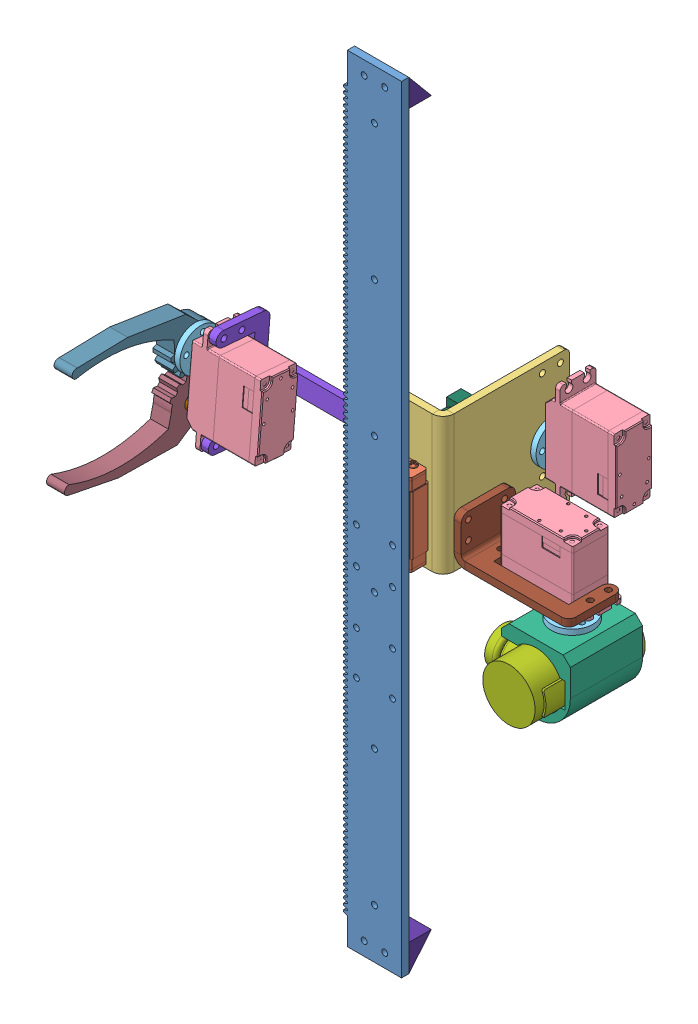
SolidWorks assembly Arm Assembly, configuration 預設. Lengths in mm.
23 component instances, 17 part files, 77 mates.
Components (placement in the parent):
- horrizontal rack-1: horrizontal rack [預設] at (0 0 -4) x (0 1 0) z (1 0 0) size (430 4 32.25)
- MGN12H-3: MGN12H [Default] at (0 -2.634 -4) x (1 0 0) z (0 1 0) size (27 10 48.55)
- horrizotal servo frame-1: horrizotal servo frame [預設] at (15 -28.634 -18) x (0 1 0) z (0 0 -1) size (75.71 38 70)
- UART Servo-4: UART Servo [預設] at (55.75 -17.934 -44.05) x (-1 0 0) z (0 -1 0) size (56 22.53 44.45)
- SMS Servo Disc-4: SMS Servo Disc [預設] at (65.425 -39.384 -44.05) x (0.954716 0 0.297519) z (0 1 0) size (23 23 6)
- Camera Mount 2-1: Camera Mount 2 [預設] at (65.425 -58.384 -24.05) x (0 1 0) z (0 0 -1) size (38 47 40)
- LifeCam Studio-2: LifeCam Studio [Default] at (65.425 -58.384 -70.05) x (0.017996 0.999838 0) z (0 0 -1) size (29 41 61)
- UART Servo-5: UART Servo [預設] at (42.45 17.321 -77) x (0 1 0) z (-1 0 0) size (56 22.53 44.45)
- gripper servo frame-2: gripper servo frame [預設] at (-91.15 -14.2051 5.1529) x (0 0.996386 -0.084938) z (1 0 0) size (57.5 85 108.15)
- UART Servo-6: UART Servo [預設] at (-84.45 13.6384 -6.705) x (0 -0.996386 0.084938) z (-1 0 0) size (56 22.53 44.45)
- gripper right part-1: gripper right part [預設] at (-107.75 -3.5402 -21.8506) x (0 0.996386 -0.084938) z (1 0 0) size (27.08 24.17 3)
- M3x5mm_toothed_plastic-4: M3x5mm_toothed_plastic [預設] at (-91.15 15.4709 -23.4712) x (0 -0.820288 0.57195) z (-1 0 0) size (5.77 5 11)
- SMS Servo Disc-5: SMS Servo Disc [預設] at (-106.75 23.2784 -7.5267) x (0 0.154092 0.988056) z (1 0 0) size (23 23 6)
- cam servo frame-2: cam servo frame [預設] at (27 -24.634 -53.05) x (1 0 0) z (0 1 0) size (63.5 30 25)
- MGNR12X400mm-1: MGNR12X400mm [Default] at (0 200 -8) x (-1 0 0) z (0 -1 0) size (12 8 400)
- gear gripper left-1: gear gripper left [預設] at (-116.75 -8.9582 7.3711) x (0 0.999873 -0.015967) z (1 0 0) size (30.5 83.97 10)
- gear gripper right-1: gear gripper right [預設] at (-106.75 32.198 4.2394) x (0 -0.988056 0.154092) z (-1 0 0) size (30.51 84.01 10)
- CHR-GM25-370-1: CHR-GM25-370 [預設] at (-26.35 -12.634 -73.8) x (-0.000569 1 0) z (0 0 1) size (27.5 25 72.5)
- mg25 moter mount-1: mg25 moter mount [預設] at (-10 -12.634 -21) x (0 1 0) z (0 0 -1) size (36 52.35 3)
- SMS Servo Disc-8: SMS Servo Disc [預設] at (21 7.646 -77) x (0 -1 0.000402) z (1 0 0) size (23 23 6)
- M3x5mm_toothed_plastic-5: M3x5mm_toothed_plastic [預設] at (-96.15 15.4709 -23.4712) x (0 -0.820288 0.57195) z (-1 0 0) size (5.77 5 11)
- limit block-1: limit block [預設] at (-15 -200 -4) x (0 -1 0) z (1 0 0) size (15 12.5 30)
- limit block-2: limit block [預設] at (15 200 -4) x (0 1 0) z (-1 0 0) size (15 12.5 30)
Mates (geometry in assembly coordinates):
- 重合/共線/共點1: coincident: point of Chassis-1/Chassis Top Frame-1
- 重合/共線/共點2: coincident anti-aligned: plane of Chassis-1/Chassis Down Frame-1 through (0 0 147.2243) normal (0 -1 0)
- 重合/共線/共點3: coincident anti-aligned: plane of Chassis-1/Chassis Top Frame-1 through (85 72 0) normal (0 0 -1)
- 重合/共線/共點4: coincident anti-aligned: plane of Chassis-1/Chassis Top Frame-1 through (0 72 147.2243) normal (0 1 0); plane of V-Slot 40x40x300 Linear Rail-1 through (0 72 50) normal (0 -1 0)
- 同軸心1: concentric aligned: circle of Chassis-1/Chassis Top Frame-1; circle of V-Slot 40x40x300 Linear Rail-1
- 同軸心2: concentric anti-aligned: circle of Chassis-1/Chassis Top Frame-1; circle of V-Slot 40x40x300 Linear Rail-1
- 平行相距14: distance = 44 mm anti-aligned: plane of Chassis-1/Chassis Top Frame-1 through (0 72 147.2243) normal (0 1 0); plane of r20 servo case-2 through (10 116 60) normal (0 -1 0)
- 同軸心51: concentric aligned: circle of Servo Hub-2; circle of r20-1
- 重合/共線/共點58: coincident anti-aligned: plane of Servo Hub-2 through (-32.67 83.45 42.755) normal (0 1 0); plane of r20-1 through (-32.67 83.45 42.755) normal (0 -1 0)
- 平行22: parallel anti-aligned: line of horrizontal rack-1 through (149.665 369.55 -6) axis (-1 0 0); line of MGN12H-300-2/MGNR12-1 through (-150.335 358.0118 -14) axis (1 0 0)
- 重合/共線/共點104: coincident anti-aligned: plane of horrizontal rack-1 through (0 354.55 -6) normal (0 0 -1); plane of MGN12H-300-2/MGNR12-1 through (-150.335 346.3118 -6) normal (0 0 1)
- 重合/共線/共點105: coincident aligned: plane of horrizontal rack-1 through (149.665 354.55 -3) normal (1 0 0); plane of MGN12H-300-2/MGNR12-1 through (149.665 358.3118 -12) normal (1 0 0)
- 同軸心93: concentric anti-aligned: circle of MGN12H-300-2/MGNR12-1; circle of MGN12H-3
- 同軸心94: concentric aligned: cylinder of MGN12H-300-2/MGNR12-1; cylinder of MGN12H-3 through (-510.5136 559.1395 -370.2037) axis (-0.015138 -0.976168 0.216489) radius 0.559
- 同軸心98: concentric anti-aligned: circle of horrizontal rack-1; circle of MGN12H-300-2/MGNR12-1
- 同軸心104: concentric anti-aligned: circle of MGN12H-3; circle of horrizotal servo frame-1
- 同軸心105: concentric anti-aligned: circle of MGN12H-3; circle of horrizotal servo frame-1
- 同軸心112: concentric aligned: circle of UART Servo-4; circle of SMS Servo Disc-4
- 重合/共線/共點115: coincident anti-aligned: plane of UART Servo-4 through (65.425 -39.339 -44.05) normal (0 -1 0); plane of SMS Servo Disc-4 through (65.425 -39.339 -44.05) normal (0 1 0)
- 同軸心120: concentric anti-aligned: circle of SMS Servo Disc-4; circle of Camera Mount 2-1
- 重合/共線/共點118: coincident anti-aligned: plane of SMS Servo Disc-4 through (65.425 -40.839 -44.05) normal (0 -1 0); plane of Camera Mount 2-1 through (84.425 -40.839 -64.05) normal (0 1 0)
- 同軸心125: concentric aligned: cylinder of Camera Mount 2-1 through (65.425 -59.839 -24.049) axis (0 0 -1) radius 15; cylinder of LifeCam Studio-2 through (65.425 -59.839 -31.05) axis (0 0 -1) radius 14.5
- 重合/共線/共點123: coincident anti-aligned: plane of Camera Mount 2-1 through (65.425 -59.839 -44.05) normal (0 0 1); plane of LifeCam Studio-2 through (81.8199 -65.885 -44.05) normal (0 0 -1)
- 重合/共線/共點124: coincident: plane of Camera Mount 2-1 through (81.425 -66.839 -44.05) normal (0 1 0); line of LifeCam Studio-2 through (79.2543 -66.839 -15.05) axis (0 0 -1)
- 平行25: parallel: plane of gripper servo frame-2; line of gripper right part-1 through (-106.75 18.021 -135) axis (0 -1 0)
- 同軸心151: concentric anti-aligned: circle of UART Servo-6; circle of SMS Servo Disc-5
- 重合/共線/共點144: coincident anti-aligned: plane of MGN12H-3 through (-13.5 12.111 -17) normal (0 0 -1); plane of horrizotal servo frame-1 through (15 -30.089 -17) normal (0 0 1)
- 同軸心160: concentric aligned: circle of MGN12H-3; cylinder of MGNR12X400mm-1 through (6 -200 -10) axis (0 1 0) radius 0.559
- 同軸心161: concentric aligned: circle of MGN12H-3; cylinder of MGNR12X400mm-1 through (-6 -200 -10) axis (0 1 0) radius 0.559
- 同軸心171: concentric aligned: cylinder of SMS Servo Disc-5 through (-103.75 -11.0946 -145.0846) axis (-1 0 0) radius 1.5; circle of gear gripper right-1
- 同軸心173: concentric anti-aligned: circle of SMS Servo Disc-5; circle of gear gripper right-1
- 重合/共線/共點166: coincident anti-aligned: plane of gripper right part-1 through (-106.75 22.021 -131) normal (-1 0 0); plane of gear gripper left-1 through (-106.75 11.8045 -157.8294) normal (1 0 0)
- 同軸心174: concentric anti-aligned: circle of gripper right part-1; circle of gear gripper left-1
- 齒輪結合1: gear = 3.2 : 3.2 mm: cylinder of gear gripper left-1 through (-106.75 22.021 -147.17) axis (-1 0 0) radius 1.6; cylinder of gear gripper right-1 through (-106.75 -3.484 -147.55) axis (-1 0 0) radius 1.6
- 重合/共線/共點169: coincident anti-aligned: plane of UART Servo-4 through (75.75 -26.089 -54.05) normal (0 1 0); plane of cam servo frame-2 through (27 -26.089 -53.05) normal (0 -1 0)
- 重合/共線/共點170: coincident anti-aligned: plane of horrizotal servo frame-1 through (21 -30.089 -18) normal (1 0 0); plane of cam servo frame-2 through (21 -26.089 -53.05) normal (-1 0 0)
- 同軸心181: concentric aligned: circle of horrizotal servo frame-1; circle of cam servo frame-2
- 同軸心182: concentric aligned: circle of horrizotal servo frame-1; circle of cam servo frame-2
- 同軸心184: concentric aligned: cylinder of horrizotal servo frame-1 through (10 -14.089 -21) axis (0 0 -1) radius 1.6; circle of mg25 moter mount-1
- 同軸心185: concentric aligned: circle of horrizotal servo frame-1; circle of mg25 moter mount-1
- 重合/共線/共點177: coincident anti-aligned: plane of horrizotal servo frame-1 through (15 -30.089 -21) normal (0 0 -1); plane of mg25 moter mount-1 through (-26.35 -14.089 -21) normal (0 0 1)
- 同軸心186: concentric aligned: cylinder of CHR-GM25-370-1 through (-26.35 -14.089 -12) axis (0 0 -1) radius 2; cylinder of mg25 moter mount-1 through (-26.35 -14.089 -24) axis (0 0 -1) radius 4
- 重合/共線/共點179: coincident anti-aligned: plane of CHR-GM25-370-1 through (-26.35 -14.089 -24) normal (0 0 1); plane of mg25 moter mount-1 through (-26.35 -14.089 -24) normal (0 0 -1)
- 重合/共線/共點180: coincident anti-aligned: plane of UART Servo-6 through (-100.75 6.191 -147.55) normal (-1 0 0); plane of SMS Servo Disc-5 through (-100.75 -3.484 -147.55) normal (1 0 0)
- 重合/共線/共點181: coincident anti-aligned: plane of SMS Servo Disc-5 through (-106.75 -3.484 -147.55) normal (-1 0 0); plane of gear gripper right-1 through (-106.75 6.7261 -158.2155) normal (1 0 0)
- 重合/共線/共點182: coincident anti-aligned: plane of gripper servo frame-2 through (-91.15 34.941 -157) normal (-1 0 0); plane of M3x5mm_toothed_plastic-4 through (-91.15 2.941 -131) normal (1 0 0)
- 同軸心191: concentric aligned: circle of horrizotal servo frame-1; circle of UART Servo-5
- 重合/共線/共點187: coincident anti-aligned: plane of UART Servo-5 through (22.5 6.191 -77) normal (-1 0 0); plane of SMS Servo Disc-8 through (22.5 6.191 -77) normal (1 0 0)
- 平行28: parallel: line of horrizotal servo frame-1 through (17 -27.089 -87) axis (0 1 0); plane of UART Servo-5 through (43.6 15.866 -87) normal (0 0 -1)
- 重合/共線/共點188: coincident anti-aligned: plane of horrizotal servo frame-1 through (21 -30.089 -18) normal (1 0 0); plane of SMS Servo Disc-8 through (21 6.191 -77) normal (-1 0 0)
- 重合/共線/共點191: coincident anti-aligned: plane of horrizotal servo frame-1 through (17 -30.089 -18) normal (-1 0 0); plane of gripper servo frame-2 through (17 34.941 -157) normal (1 0 0)
- 同軸心203: concentric aligned: circle of horrizotal servo frame-1; circle of SMS Servo Disc-8
- 限制距離10: limit distance = 179.934 mm aligned: plane of MGNR12X400mm-1 through (-6 200 -10) normal (0 1 0); plane of MGN12H-3 through (6 20.066 -10) normal (0 1 0)
- 重合/共線/共點192: coincident anti-aligned: plane of gripper servo frame-2 through (-91.15 34.941 -157) normal (-1 0 0); plane of UART Servo-6 through (-91.15 -13.809 -157.55) normal (1 0 0)
- 重合/共線/共點193: coincident anti-aligned: plane of M3x5mm_toothed_plastic-4 through (-96.15 2.941 -131) normal (-1 0 0); plane of M3x5mm_toothed_plastic-5 through (-96.15 2.941 -131) normal (1 0 0)
- 同軸心204: concentric aligned: circle of M3x5mm_toothed_plastic-4; cylinder of M3x5mm_toothed_plastic-5 through (-90.15 2.941 -131) axis (-1 0 0) radius 1.5
- 重合/共線/共點195: coincident aligned: plane of gear gripper left-1 through (-116.75 11.8045 -157.8294) normal (-1 0 0); plane of gear gripper right-1 through (-116.75 6.7261 -158.2155) normal (-1 0 0)
- 同軸心207: concentric anti-aligned: circle of gripper servo frame-2; circle of UART Servo-6
- 同軸心208: concentric anti-aligned: cylinder of gripper servo frame-2 through (-91.15 -18.559 -142.55) axis (-1 0 0) radius 1.65; circle of UART Servo-6
- 同軸心209: concentric anti-aligned: cylinder of gripper servo frame-2 through (13 6.191 -77) axis (-1 0 0) radius 1.25; circle of SMS Servo Disc-8
- 同軸心210: concentric anti-aligned: circle of gripper right part-1; circle of M3x5mm_toothed_plastic-5
- 同軸心211: concentric anti-aligned: circle of gripper servo frame-2; circle of M3x5mm_toothed_plastic-4
- 同軸心212: concentric anti-aligned: circle of UART Servo-4; circle of cam servo frame-2
- 同軸心213: concentric anti-aligned: circle of UART Servo-4; cylinder of cam servo frame-2 through (80.5 -26.089 -49.05) axis (0 -1 0) radius 1.65
- 平行30: parallel anti-aligned: plane of Camera Mount 2-1 through (65.425 -59.839 -24.05) normal (0 0 1); plane of cam servo frame-2 through (21 -22.089 -53.05) normal (0 0 -1)
- 重合/共線/共點196: coincident anti-aligned: plane of horrizontal rack-1 through (0 0 -4) normal (0 0 -1); plane of MGNR12X400mm-1 through (6 -200 -4) normal (0 0 1)
- 同軸心214: concentric aligned: circle of horrizontal rack-1; cylinder of MGNR12X400mm-1 through (0 -187.5 -12) axis (0 0 -1) radius 1.75
- 同軸心215: concentric aligned: circle of horrizontal rack-1; cylinder of MGNR12X400mm-1 through (0 -112.5 -12) axis (0 0 -1) radius 1.75
- 同軸心219: concentric anti-aligned: circle of horrizontal rack-1; circle of limit block-1
- 同軸心220: concentric anti-aligned: circle of horrizontal rack-1; cylinder of limit block-1 through (5.7 -207.5 -34) axis (0 0 1) radius 2.1
- 重合/共線/共點198: coincident anti-aligned: plane of horrizontal rack-1 through (0 0 -4) normal (0 0 -1); plane of limit block-1 through (15 -200 -4) normal (0 0 1)
- 同軸心221: concentric anti-aligned: circle of horrizontal rack-1; circle of limit block-2
- 同軸心222: concentric aligned: circle of horrizontal rack-1; circle of limit block-2
- 重合/共線/共點199: coincident anti-aligned: plane of horrizontal rack-1 through (0 0 -4) normal (0 0 -1); plane of limit block-2 through (-15 200 -4) normal (0 0 1)
- 重合/共線/共點201: coincident aligned: plane of horrizontal rack-1 through (0 0 0) normal (0 0 1)
- 相互對稱1: symmetric aligned: plane of horrizontal rack-1 through (0 215 -4) normal (0 1 0); plane of horrizontal rack-1 through (0 -215 -4) normal (0 -1 0)
- 相互對稱2: symmetric aligned: plane of horrizontal rack-1 through (15 0 -4) normal (1 0 0); plane of horrizontal rack-1 through (-15 0 -4) normal (-1 0 0)
